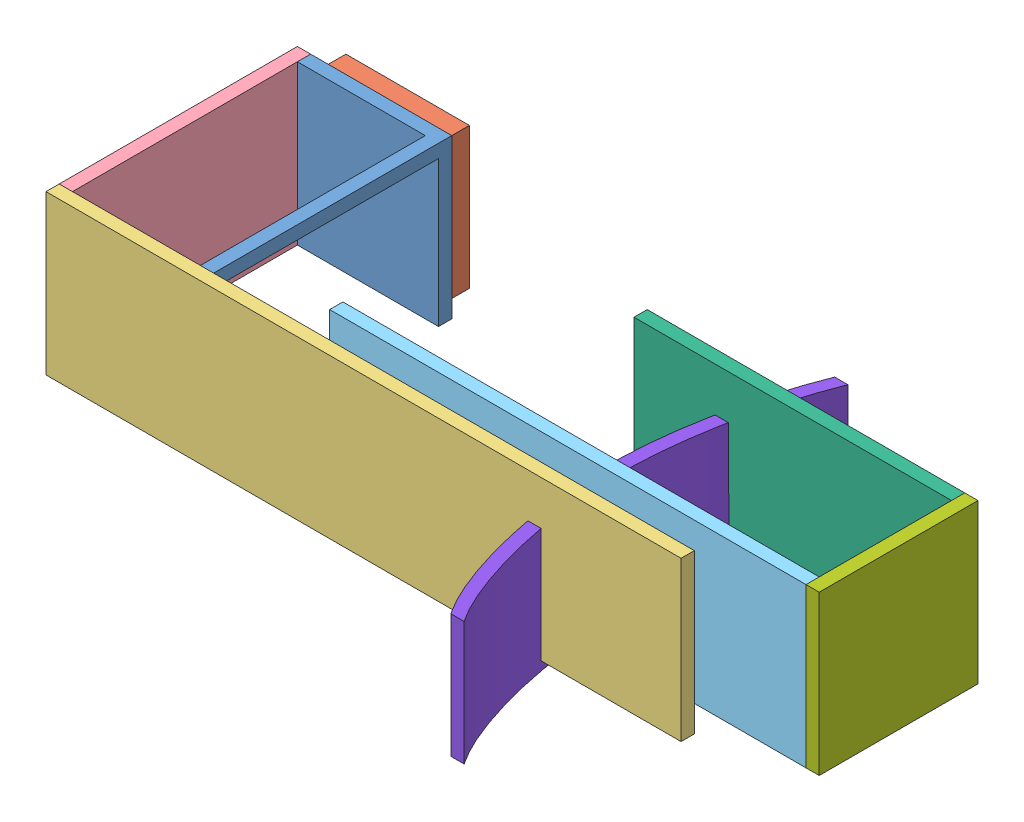
SolidWorks assembly Assembly 1, configuration Default. Lengths in mm.
Overall size (2112.27 482.6 1143).
8 component instances, 8 part files, 0 mates.
Components (placement in the parent):
- Part 1-1: Part 1 [Default] at (-25.4 -25.4 76.2) size (406.4 457.2 685.8)
- Part 1-1-1: Part 1-1 [Default] at origin size (355.6 406.4 76.2)
- Part 1-2-1: Part 1-2 [Default] at (1765.3 -25.4 762) size (1828.8 457.2 38.1)
- Part 1-3-1: Part 1-3 [Default] at (-63.5 431.8 76.2) size (38.1 457.2 685.8)
- Part 1-4-1: Part 1-4 [Default] at (2010.6701 -25.4 647.7) size (1371.6 457.2 38.1)
- Part 1-5-1: Part 1-5 [Default] at (2010.6701 -25.4 228.6) size (914.4 457.2 38.1)
- Part 1-6-1: Part 1-6 [Default] at (2010.6701 431.8 228.6) size (38.1 457.2 457.2)
- Part 1-7-1: Part 1-7 [Default] at (1407.5698 304.8 0) size (249.86 355.6 1143)
